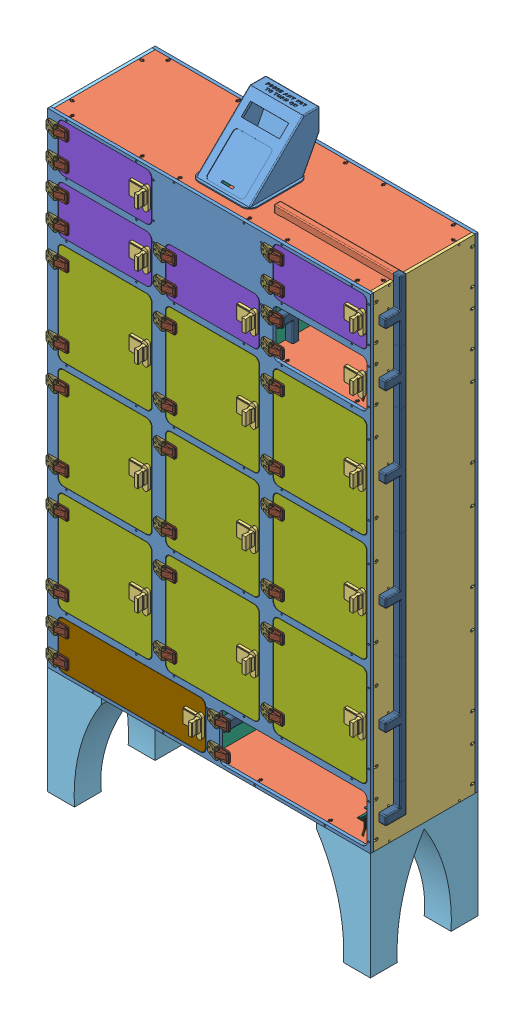
SolidWorks assembly BigAssemb, configuration Default. Lengths in mm.
Overall size (613.29 1199.98 221).
252 component instances, 24 part files, 113 mates.
Components (placement in the parent):
- LargeFront-1: LargeFront [Default] at origin size (600 900 5.8)
- floor + roof-1: floor + roof [only one passthru] at (5.8 100 -188.4) size (588.4 5.8 188.4)
- floor + roof-2: floor + roof [Default] at (5.8 300 -188.4) size (588.4 5.8 188.4)
- floor + roof-3: floor + roof [Default] at (5.8 500 -188.4) size (588.4 5.8 188.4)
- floor + roof-4: floor + roof [Default] at (5.8 700 -188.4) size (588.4 5.8 188.4)
- floor + roof-5: floor + roof [Default] at (5.8 800 -188.4) size (588.4 5.8 188.4)
- right side-1: right side [Default] at (594.2 0 0) size (5.8 900 188.4)
- right(INSIDE200mm)-1: right(INSIDE200mm) [Default] at (194.2 200 -94.2) size (5.8 194.2 188.4)
- right(INSIDE200mm)-2: right(INSIDE200mm) [Default] at (194.2 400 -94.2) size (5.8 194.2 188.4)
- right(INSIDE200mm)-3: right(INSIDE200mm) [Default] at (194.2 600 -94.2) size (5.8 194.2 188.4)
- right(INSIDE200mm)-4: right(INSIDE200mm) [Default] at (394.2 200 -94.2) size (5.8 194.2 188.4)
- right(INSIDE200mm)-5: right(INSIDE200mm) [Default] at (394.2 400 -94.2) size (5.8 194.2 188.4)
- right(INSIDE200mm)-6: right(INSIDE200mm) [Default] at (394.2 600 -94.2) size (5.8 194.2 188.4)
- sides-2: sides [right] at (5.8 0 -188.4) x (-1 0 0) z (0 0 -1) size (5.8 900 188.4)
- right(INSIDE100mm)-7: right(INSIDE100mm) [Default] at (194.2 750 -94.2) size (5.8 94.2 188.4)
- right(INSIDE100mm)-8: right(INSIDE100mm) [top(-5.8)] at (194.2 850 -94.2) size (5.8 88.4 188.4)
- right(INSIDE100mm)-9: right(INSIDE100mm) [Default] at (394.2 750 -94.2) size (5.8 94.2 188.4)
- right(INSIDE100mm)-10: right(INSIDE100mm) [top(no servo)] at (394.2 850 -94.2) size (5.8 88.4 188.4)
- right(INSIDE100mm)-11: right(INSIDE100mm) [Default] at (294.2 50 -94.2) size (5.8 94.2 188.4)
- LargeFront-2: LargeFront [back] at (0 0 -194.2) size (600 900 5.8)
- door(200x200)-1: door(200x200) [Default] at (106.7 200 0) size (173 187.4 5.8)
- door(200x200)-2: door(200x200) [Default] at (106.7 400 0) size (173 187.4 5.8)
- door(200x200)-3: door(200x200) [Default] at (106.7 600 0) size (173 187.4 5.8)
- door(200x200)-4: door(200x200) [Default] at (306.7 200 0) size (173 187.4 5.8)
- door(200x200)-5: door(200x200) [Default] at (306.7 400 0) size (173 187.4 5.8)
- door(200x200)-6: door(200x200) [Default] at (306.7 600 0) size (173 187.4 5.8)
- door(200x200)-7: door(200x200) [Default] at (506.7 200 0) size (173 187.4 5.8)
- door(200x200)-8: door(200x200) [Default] at (506.7 400 0) size (173 187.4 5.8)
- door(200x200)-9: door(200x200) [Default] at (506.7 600 0) size (173 187.4 5.8)
- door(100x200)-1: door(100x200) [Default] at (20.2 750 0) size (173 88.4 5.8)
- door(100x200)-2: door(100x200) [Default] at (20.2 850 0) size (173 88.4 5.8)
- door(100x200)-3: door(100x200) [Default] at (220.2 750 0) size (173 88.4 5.8)
- door(100x200)-4: door(100x200) [Default] at (420.2 750 0) size (173 88.4 5.8) (hidden)
- door(100x200)-5: door(100x200) [Default] at (420.2 850 0) size (173 88.4 5.8)
- door(100x300)-1: door(100x300) [Default] at (20.2 50 0) size (273 87.4 5.8)
- door(100x300)-2: door(100x300) [Default] at (320.2 50 0) size (273 87.4 5.8) (hidden)
- floor + roof-6: floor + roof [roof] at (5.8 894.2 -188.4) size (588.4 5.8 188.4)
- Conduit-9: Conduit [Default] at (600 194.025 -12.141) x (0 0 -1) z (1 0 0) size (38.8 200 13)
- Conduit-10: Conduit [Default] at (600 394.025 -12.141) x (0 0 -1) z (1 0 0) size (38.8 200 13)
- Conduit-11: Conduit [Default] at (600 594.025 -12.141) x (0 0 -1) z (1 0 0) size (38.8 200 13)
- Conduit-12: Conduit [100] at (600 744.025 -12.141) x (0 0 -1) z (1 0 0) size (38.8 100 13)
- Conduit-13: Conduit [top100] at (600 844.025 -12.141) x (0 0 -1) z (1 0 0) size (38.8 113 13)
- Conduit-14: Conduit [Default] at (400 194.025 -12.141) x (0 0 -1) z (1 0 0) size (38.8 200 13)
- Conduit-15: Conduit [Inside200] at (200 194.025 -12.141) x (0 0 -1) z (1 0 0) size (38.8 108.15 13)
- Conduit-17: Conduit [Default] at (400 394.025 -12.141) x (0 0 -1) z (1 0 0) size (38.8 200 13)
- Conduit-18: Conduit [Default] at (200 394.025 -12.141) x (0 0 -1) z (1 0 0) size (38.8 200 13)
- Conduit-20: Conduit [Default] at (400 594.025 -12.141) x (0 0 -1) z (1 0 0) size (38.8 200 13)
- Conduit-21: Conduit [Default] at (200 594.025 -12.141) x (0 0 -1) z (1 0 0) size (38.8 200 13)
- Conduit-23: Conduit [100] at (400 744.025 -12.141) x (0 0 -1) z (1 0 0) size (38.8 100 13)
- Conduit-24: Conduit [100] at (200 744.025 -12.141) x (0 0 -1) z (1 0 0) size (38.8 100 13)
- Conduit-25: Conduit [inside left] at (200 844.025 -12.141) x (0 0 -1) z (1 0 0) size (38.8 71.15 13)
- Conduit-26: Conduit [inside right] at (400 844.025 -12.141) x (0 0 -1) z (1 0 0) size (12 71.15 20.3)
- Conduit-27: Conduit [bottom100] at (600 44.025 -12.141) x (0 0 -1) z (1 0 0) size (38.8 58.15 13)
- hinge in-2: hinge in [Default] at (27.9167 96.333 5.8) x (0 1 0) z (0 0 1) size (20 23.4 8)
- hinge in-3: hinge in [Default] at (27.9167 45.333 6.3536) x (0 1 0) z (0 0 1) size (20 23.4 8)
- hinge in-4: hinge in [Default] at (27.9167 155.833 5.8) x (0 1 0) z (0 0 1) size (20 23.4 8)
- hinge in-5: hinge in [Default] at (27.9167 745.333 5.8) x (0 1 0) z (0 0 1) size (20 23.4 8)
- hinge in-6: hinge in [Default] at (27.9167 796.333 6.3536) x (0 1 0) z (0 0 1) size (20 23.4 8)
- hinge in-7: hinge in [Default] at (27.9167 285.833 5.8) x (0 1 0) z (0 0 1) size (20 23.4 8)
- hinge in-8: hinge in [Default] at (327.9167 96.333 5.8) x (0 1 0) z (0 0 1) size (20 23.4 8)
- hinge in-9: hinge in [Default] at (327.9167 45.333 6.3536) x (0 1 0) z (0 0 1) size (20 23.4 8)
- hinge in-10: hinge in [Default] at (27.9167 485.833 5.8) x (0 1 0) z (0 0 1) size (20 23.4 8)
- hinge in-11: hinge in [Default] at (27.9167 685.833 5.8) x (0 1 0) z (0 0 1) size (20 23.4 8)
- hinge in-12: hinge in [Default] at (227.9167 285.833 5.8) x (0 1 0) z (0 0 1) size (20 23.4 8)
- hinge in-13: hinge in [Default] at (227.9167 485.833 5.8) x (0 1 0) z (0 0 1) size (20 23.4 8)
- hinge in-14: hinge in [Default] at (227.9167 685.833 5.8) x (0 1 0) z (0 0 1) size (20 23.4 8)
- hinge in-15: hinge in [Default] at (427.9167 285.833 5.8) x (0 1 0) z (0 0 1) size (20 23.4 8)
- hinge in-16: hinge in [Default] at (427.9167 485.833 5.8) x (0 1 0) z (0 0 1) size (20 23.4 8)
- hinge in-17: hinge in [Default] at (427.9167 685.833 5.8) x (0 1 0) z (0 0 1) size (20 23.4 8)
- hinge in-18: hinge in [Default] at (27.9167 355.833 5.8) x (0 1 0) z (0 0 1) size (20 23.4 8)
- hinge in-19: hinge in [Default] at (27.9167 555.833 5.8) x (0 1 0) z (0 0 1) size (20 23.4 8)
- hinge in-20: hinge in [Default] at (227.9167 155.833 5.8) x (0 1 0) z (0 0 1) size (20 23.4 8)
- hinge in-21: hinge in [Default] at (227.9167 355.833 5.8) x (0 1 0) z (0 0 1) size (20 23.4 8)
- hinge in-22: hinge in [Default] at (227.9167 555.833 5.8) x (0 1 0) z (0 0 1) size (20 23.4 8)
- hinge in-23: hinge in [Default] at (427.9167 155.833 5.8) x (0 1 0) z (0 0 1) size (20 23.4 8)
- hinge in-24: hinge in [Default] at (427.9167 355.833 5.8) x (0 1 0) z (0 0 1) size (20 23.4 8)
- hinge in-25: hinge in [Default] at (427.9167 555.833 5.8) x (0 1 0) z (0 0 1) size (20 23.4 8)
- hinge in-26: hinge in [Default] at (27.9167 896.333 6.3536) x (0 1 0) z (0 0 1) size (20 23.4 8)
- hinge in-27: hinge in [Default] at (227.9167 796.333 6.3536) x (0 1 0) z (0 0 1) size (20 23.4 8)
- hinge in-28: hinge in [Default] at (427.9167 796.333 6.3536) x (0 1 0) z (0 0 1) size (20 23.4 8)
- hinge in-29: hinge in [Default] at (427.9167 896.333 6.3536) x (0 1 0) z (0 0 1) size (20 23.4 8)
- hinge in-30: hinge in [Default] at (27.9167 845.333 5.8) x (0 1 0) z (0 0 1) size (20 23.4 8)
- hinge in-31: hinge in [Default] at (227.9167 745.333 5.8) x (0 1 0) z (0 0 1) size (20 23.4 8)
- hinge in-32: hinge in [Default] at (427.9167 745.333 5.8) x (0 1 0) z (0 0 1) size (20 23.4 8)
- hinge in-33: hinge in [Default] at (427.9167 845.333 5.8) x (0 1 0) z (0 0 1) size (20 23.4 8)
- hinge out-offset-2: hinge out-offset [Default] at (11.9978 3.6698 5.8) x (0 -1 0) z (0 0 1) size (20 22.9 8)
- hinge out-offset-11: hinge out-offset [Default] at (11.9978 54.6698 5.8) x (0 -1 0) z (0 0 1) size (20 22.9 8)
- hinge out-offset-13: hinge out-offset [Default] at (11.9978 114.1698 5.8) x (0 -1 0) z (0 0 1) size (20 22.9 8)
- hinge out-offset-27: hinge out-offset [Default] at (11.9978 244.1698 5.8) x (0 -1 0) z (0 0 1) size (20 22.9 8)
- hinge out-offset-36: hinge out-offset [Default] at (11.9978 703.6698 5.8) x (0 -1 0) z (0 0 1) size (20 22.9 8)
- hinge out-offset-41: hinge out-offset [Default] at (11.9978 754.6698 5.8) x (0 -1 0) z (0 0 1) size (20 22.9 8)
- hinge out-offset-12: hinge out-offset [Default] at (311.9978 54.6698 5.8) x (0 -1 0) z (0 0 1) size (20 22.9 8)
- hinge out-offset-10: hinge out-offset [Default] at (311.9978 3.6698 5.8) x (0 -1 0) z (0 0 1) size (20 22.9 8)
- hinge out-offset-28: hinge out-offset [Default] at (11.9978 444.1698 5.8) x (0 -1 0) z (0 0 1) size (20 22.9 8)
- hinge out-offset-29: hinge out-offset [Default] at (11.9978 644.1698 5.8) x (0 -1 0) z (0 0 1) size (20 22.9 8)
- hinge out-offset-30: hinge out-offset [Default] at (211.9978 244.1698 5.8) x (0 -1 0) z (0 0 1) size (20 22.9 8)
- hinge out-offset-31: hinge out-offset [Default] at (211.9978 444.1698 5.8) x (0 -1 0) z (0 0 1) size (20 22.9 8)
- hinge out-offset-32: hinge out-offset [Default] at (211.9978 644.1698 5.8) x (0 -1 0) z (0 0 1) size (20 22.9 8)
- hinge out-offset-33: hinge out-offset [Default] at (411.9978 244.1698 5.8) x (0 -1 0) z (0 0 1) size (20 22.9 8)
- hinge out-offset-34: hinge out-offset [Default] at (411.9978 444.1698 5.8) x (0 -1 0) z (0 0 1) size (20 22.9 8)
- hinge out-offset-35: hinge out-offset [Default] at (411.9978 644.1698 5.8) x (0 -1 0) z (0 0 1) size (20 22.9 8)
- hinge out-offset-19: hinge out-offset [Default] at (11.9978 314.1698 5.8) x (0 -1 0) z (0 0 1) size (20 22.9 8)
- hinge out-offset-20: hinge out-offset [Default] at (11.9978 514.1698 5.8) x (0 -1 0) z (0 0 1) size (20 22.9 8)
- hinge out-offset-21: hinge out-offset [Default] at (211.9978 114.1698 5.8) x (0 -1 0) z (0 0 1) size (20 22.9 8)
- hinge out-offset-22: hinge out-offset [Default] at (211.9978 314.1698 5.8) x (0 -1 0) z (0 0 1) size (20 22.9 8)
- hinge out-offset-23: hinge out-offset [Default] at (211.9978 514.1698 5.8) x (0 -1 0) z (0 0 1) size (20 22.9 8)
- hinge out-offset-24: hinge out-offset [Default] at (411.9978 114.1698 5.8) x (0 -1 0) z (0 0 1) size (20 22.9 8)
- hinge out-offset-25: hinge out-offset [Default] at (411.9978 314.1698 5.8) x (0 -1 0) z (0 0 1) size (20 22.9 8)
- hinge out-offset-26: hinge out-offset [Default] at (411.9978 514.1698 5.8) x (0 -1 0) z (0 0 1) size (20 22.9 8)
- hinge out-offset-37: hinge out-offset [Default] at (11.9978 803.6698 5.8) x (0 -1 0) z (0 0 1) size (20 22.9 8)
- hinge out-offset-38: hinge out-offset [Default] at (211.9978 703.6698 5.8) x (0 -1 0) z (0 0 1) size (20 22.9 8)
- hinge out-offset-39: hinge out-offset [Default] at (411.9978 703.6698 5.8) x (0 -1 0) z (0 0 1) size (20 22.9 8)
- hinge out-offset-40: hinge out-offset [Default] at (411.9978 803.6698 5.8) x (0 -1 0) z (0 0 1) size (20 22.9 8)
- hinge out-offset-42: hinge out-offset [Default] at (11.9978 854.6698 5.8) x (0 -1 0) z (0 0 1) size (20 22.9 8)
- hinge out-offset-43: hinge out-offset [Default] at (211.9978 754.6698 5.8) x (0 -1 0) z (0 0 1) size (20 22.9 8)
- hinge out-offset-44: hinge out-offset [Default] at (411.9978 754.6698 5.8) x (0 -1 0) z (0 0 1) size (20 22.9 8)
- hinge out-offset-45: hinge out-offset [Default] at (411.9978 854.6698 5.8) x (0 -1 0) z (0 0 1) size (20 22.9 8)
- floor + roof-7: floor + roof [floor] at (5.8 0 -188.4) size (588.4 5.8 188.4)
- LatchAssemb-1: LatchAssemb [Default] at (610.86 844 -34.641) x (0 0 1) z (0 -1 0) size (59.33 32.5 49.06)
  - servo-1: servo [Default] at origin size (32.1 30.61 12)
  - latch shroud-1: latch shroud [Default] at (-4.95 23.16 0) x (0 1 0) z (-1 0 0) size (13.45 37.8 42.25)
  - latch-1: latch [Default] at (40.4868 27.24 -1.4888) x (0 -1 0) z (0.999992 0 -0.004045) size (4.1 23.3 53.57)
  - servo link-1: servo link [Default] at (5.835 27.45 -6) x (0 1 0) z (-0.897729 0 -0.440549) size (9.3 13.8 26.8)
  - spring-1: spring [Default] at (7.42 23.16 -6) x (0 1 0) z (-0.999998 0 -0.001752) size (4.3 11.4 35.23)
  - Doorspring-1: Doorspring [Default] at (-0.017 30.01 0.1365) x (0.999999 0 -0.00113) z (0 1 0) size (12.89 29.53 2.55)
- LatchAssemb-2: LatchAssemb [Default] at (210.86 844 -34.641) x (0 0 1) z (0 -1 0) size (59.33 32.5 49.06)
  - servo-1: servo [Default] at origin size (32.1 30.61 12)
  - latch shroud-1: latch shroud [Default] at (-4.95 23.16 0) x (0 1 0) z (-1 0 0) size (13.45 37.8 42.25)
  - latch-1: latch [Default] at (40.4868 27.24 -1.4888) x (0 -1 0) z (0.999992 0 -0.004045) size (4.1 23.3 53.57)
  - servo link-1: servo link [Default] at (5.835 27.45 -6) x (0 1 0) z (-0.897729 0 -0.440549) size (9.3 13.8 26.8)
  - spring-1: spring [Default] at (7.42 23.16 -6) x (0 1 0) z (-0.999998 0 -0.001752) size (4.3 11.4 35.23)
  - Doorspring-1: Doorspring [Default] at (-0.017 30.01 0.1365) x (0.999999 0 -0.00113) z (0 1 0) size (12.89 29.53 2.55)
- LatchAssemb-3: LatchAssemb [Default] at (610.86 744 -34.641) x (0 0 1) z (0 -1 0) size (59.33 32.5 49.06)
  - servo-1: servo [Default] at origin size (32.1 30.61 12)
  - latch shroud-1: latch shroud [Default] at (-4.95 23.16 0) x (0 1 0) z (-1 0 0) size (13.45 37.8 42.25)
  - latch-1: latch [Default] at (40.4868 27.24 -1.4888) x (0 -1 0) z (0.999992 0 -0.004045) size (4.1 23.3 53.57)
  - servo link-1: servo link [Default] at (5.835 27.45 -6) x (0 1 0) z (-0.897729 0 -0.440549) size (9.3 13.8 26.8)
  - spring-1: spring [Default] at (7.42 23.16 -6) x (0 1 0) z (-0.999998 0 -0.001752) size (4.3 11.4 35.23)
  - Doorspring-1: Doorspring [Default] at (-0.017 30.01 0.1365) x (0.999999 0 -0.00113) z (0 1 0) size (12.89 29.53 2.55)
- LatchAssemb-4: LatchAssemb [Default] at (410.86 744 -34.641) x (0 0 1) z (0 -1 0) size (59.33 32.5 49.06)
  - servo-1: servo [Default] at origin size (32.1 30.61 12)
  - latch shroud-1: latch shroud [Default] at (-4.95 23.16 0) x (0 1 0) z (-1 0 0) size (13.45 37.8 42.25)
  - latch-1: latch [Default] at (40.4868 27.24 -1.4888) x (0 -1 0) z (0.999992 0 -0.004045) size (4.1 23.3 53.57)
  - servo link-1: servo link [Default] at (5.835 27.45 -6) x (0 1 0) z (-0.897729 0 -0.440549) size (9.3 13.8 26.8)
  - spring-1: spring [Default] at (7.42 23.16 -6) x (0 1 0) z (-0.999998 0 -0.001752) size (4.3 11.4 35.23)
  - Doorspring-1: Doorspring [Default] at (-0.017 30.01 0.1365) x (0.999999 0 -0.00113) z (0 1 0) size (12.89 29.53 2.55)
- LatchAssemb-5: LatchAssemb [Default] at (210.86 744 -34.641) x (0 0 1) z (0 -1 0) size (59.33 32.5 49.06)
  - servo-1: servo [Default] at origin size (32.1 30.61 12)
  - latch shroud-1: latch shroud [Default] at (-4.95 23.16 0) x (0 1 0) z (-1 0 0) size (13.45 37.8 42.25)
  - latch-1: latch [Default] at (40.4868 27.24 -1.4888) x (0 -1 0) z (0.999992 0 -0.004045) size (4.1 23.3 53.57)
  - servo link-1: servo link [Default] at (5.835 27.45 -6) x (0 1 0) z (-0.897729 0 -0.440549) size (9.3 13.8 26.8)
  - spring-1: spring [Default] at (7.42 23.16 -6) x (0 1 0) z (-0.999998 0 -0.001752) size (4.3 11.4 35.23)
  - Doorspring-1: Doorspring [Default] at (-0.017 30.01 0.1365) x (0.999999 0 -0.00113) z (0 1 0) size (12.89 29.53 2.55)
- ScreenMount-1: ScreenMount [Default] at (300 895.2 -70) x (-1 0 0) z (0 0 -1) size (110 107.98 135)
- topConduit-1: topConduit [Default] at (380 900.175 -38.941) size (222 18.8 12)
- knob-1: knob [Default] at (185.7 740.45 5.8) size (35 41.51 21)
- knob-2: knob [Default] at (185.7 840.45 5.8) size (35 41.51 21)
- knob-3: knob [Default] at (385.7 740.45 5.8) size (35 41.51 21)
- knob-4: knob [Default] at (585.7 740.45 5.8) size (35 41.51 21)
- knob-5: knob [Default] at (585.7 840.45 5.8) size (35 41.51 21)
- LatchAssemb-6: LatchAssemb [Default] at (310.86 44 -34.591) x (0 0 1) z (0 -1 0) size (59.33 32.5 49.06)
  - servo-1: servo [Default] at origin size (32.1 30.61 12)
  - latch shroud-1: latch shroud [Default] at (-4.95 23.16 0) x (0 1 0) z (-1 0 0) size (13.45 37.8 42.25)
  - latch-1: latch [Default] at (40.4868 27.24 -1.4888) x (0 -1 0) z (0.999992 0 -0.004045) size (4.1 23.3 53.57)
  - servo link-1: servo link [Default] at (5.835 27.45 -6) x (0 1 0) z (-0.897729 0 -0.440549) size (9.3 13.8 26.8)
  - spring-1: spring [Default] at (7.42 23.16 -6) x (0 1 0) z (-0.999998 0 -0.001752) size (4.3 11.4 35.23)
  - Doorspring-1: Doorspring [Default] at (-0.017 30.01 0.1365) x (0.999999 0 -0.00113) z (0 1 0) size (12.89 29.53 2.55)
- LatchAssemb-7: LatchAssemb [Default] at (610.86 44 -34.591) x (0 0 1) z (0 -1 0) size (59.33 32.5 49.06)
  - servo-1: servo [Default] at origin size (32.1 30.61 12)
  - latch shroud-1: latch shroud [Default] at (-4.95 23.16 0) x (0 1 0) z (-1 0 0) size (13.45 37.8 42.25)
  - latch-1: latch [Default] at (40.4868 27.24 -1.4888) x (0 -1 0) z (0.999992 0 -0.004045) size (4.1 23.3 53.57)
  - servo link-1: servo link [Default] at (5.835 27.45 -6) x (0 1 0) z (-0.897729 0 -0.440549) size (9.3 13.8 26.8)
  - spring-1: spring [Default] at (7.42 23.16 -6) x (0 1 0) z (-0.999998 0 -0.001752) size (4.3 11.4 35.23)
  - Doorspring-1: Doorspring [Default] at (-0.017 30.01 0.1365) x (0.999999 0 -0.00113) z (0 1 0) size (12.89 29.53 2.55)
- LatchAssemb-8: LatchAssemb [Default] at (210.86 194 -34.591) x (0 0 1) z (0 -1 0) size (59.33 32.5 49.06)
  - servo-1: servo [Default] at origin size (32.1 30.61 12)
  - latch shroud-1: latch shroud [Default] at (-4.95 23.16 0) x (0 1 0) z (-1 0 0) size (13.45 37.8 42.25)
  - latch-1: latch [Default] at (40.4868 27.24 -1.4888) x (0 -1 0) z (0.999992 0 -0.004045) size (4.1 23.3 53.57)
  - servo link-1: servo link [Default] at (5.835 27.45 -6) x (0 1 0) z (-0.897729 0 -0.440549) size (9.3 13.8 26.8)
  - spring-1: spring [Default] at (7.42 23.16 -6) x (0 1 0) z (-0.999998 0 -0.001752) size (4.3 11.4 35.23)
  - Doorspring-1: Doorspring [Default] at (-0.017 30.01 0.1365) x (0.999999 0 -0.00113) z (0 1 0) size (12.89 29.53 2.55)
- LatchAssemb-9: LatchAssemb [Default] at (210.86 394 -34.591) x (0 0 1) z (0 -1 0) size (59.33 32.5 49.06)
  - servo-1: servo [Default] at origin size (32.1 30.61 12)
  - latch shroud-1: latch shroud [Default] at (-4.95 23.16 0) x (0 1 0) z (-1 0 0) size (13.45 37.8 42.25)
  - latch-1: latch [Default] at (40.4868 27.24 -1.4888) x (0 -1 0) z (0.999992 0 -0.004045) size (4.1 23.3 53.57)
  - servo link-1: servo link [Default] at (5.835 27.45 -6) x (0 1 0) z (-0.897729 0 -0.440549) size (9.3 13.8 26.8)
  - spring-1: spring [Default] at (7.42 23.16 -6) x (0 1 0) z (-0.999998 0 -0.001752) size (4.3 11.4 35.23)
  - Doorspring-1: Doorspring [Default] at (-0.017 30.01 0.1365) x (0.999999 0 -0.00113) z (0 1 0) size (12.89 29.53 2.55)
- LatchAssemb-10: LatchAssemb [Default] at (210.86 594 -34.591) x (0 0 1) z (0 -1 0) size (59.33 32.5 49.06)
  - servo-1: servo [Default] at origin size (32.1 30.61 12)
  - latch shroud-1: latch shroud [Default] at (-4.95 23.16 0) x (0 1 0) z (-1 0 0) size (13.45 37.8 42.25)
  - latch-1: latch [Default] at (40.4868 27.24 -1.4888) x (0 -1 0) z (0.999992 0 -0.004045) size (4.1 23.3 53.57)
  - servo link-1: servo link [Default] at (5.835 27.45 -6) x (0 1 0) z (-0.897729 0 -0.440549) size (9.3 13.8 26.8)
  - spring-1: spring [Default] at (7.42 23.16 -6) x (0 1 0) z (-0.999998 0 -0.001752) size (4.3 11.4 35.23)
  - Doorspring-1: Doorspring [Default] at (-0.017 30.01 0.1365) x (0.999999 0 -0.00113) z (0 1 0) size (12.89 29.53 2.55)
- LatchAssemb-11: LatchAssemb [Default] at (410.86 194 -34.591) x (0 0 1) z (0 -1 0) size (59.33 32.5 49.06)
  - servo-1: servo [Default] at origin size (32.1 30.61 12)
  - latch shroud-1: latch shroud [Default] at (-4.95 23.16 0) x (0 1 0) z (-1 0 0) size (13.45 37.8 42.25)
  - latch-1: latch [Default] at (40.4868 27.24 -1.4888) x (0 -1 0) z (0.999992 0 -0.004045) size (4.1 23.3 53.57)
  - servo link-1: servo link [Default] at (5.835 27.45 -6) x (0 1 0) z (-0.897729 0 -0.440549) size (9.3 13.8 26.8)
  - spring-1: spring [Default] at (7.42 23.16 -6) x (0 1 0) z (-0.999998 0 -0.001752) size (4.3 11.4 35.23)
  - Doorspring-1: Doorspring [Default] at (-0.017 30.01 0.1365) x (0.999999 0 -0.00113) z (0 1 0) size (12.89 29.53 2.55)
- LatchAssemb-12: LatchAssemb [Default] at (410.86 394 -34.591) x (0 0 1) z (0 -1 0) size (59.33 32.5 49.06)
  - servo-1: servo [Default] at origin size (32.1 30.61 12)
  - latch shroud-1: latch shroud [Default] at (-4.95 23.16 0) x (0 1 0) z (-1 0 0) size (13.45 37.8 42.25)
  - latch-1: latch [Default] at (40.4868 27.24 -1.4888) x (0 -1 0) z (0.999992 0 -0.004045) size (4.1 23.3 53.57)
  - servo link-1: servo link [Default] at (5.835 27.45 -6) x (0 1 0) z (-0.897729 0 -0.440549) size (9.3 13.8 26.8)
  - spring-1: spring [Default] at (7.42 23.16 -6) x (0 1 0) z (-0.999998 0 -0.001752) size (4.3 11.4 35.23)
  - Doorspring-1: Doorspring [Default] at (-0.017 30.01 0.1365) x (0.999999 0 -0.00113) z (0 1 0) size (12.89 29.53 2.55)
- LatchAssemb-13: LatchAssemb [Default] at (410.86 594 -34.591) x (0 0 1) z (0 -1 0) size (59.33 32.5 49.06)
  - servo-1: servo [Default] at origin size (32.1 30.61 12)
  - latch shroud-1: latch shroud [Default] at (-4.95 23.16 0) x (0 1 0) z (-1 0 0) size (13.45 37.8 42.25)
  - latch-1: latch [Default] at (40.4868 27.24 -1.4888) x (0 -1 0) z (0.999992 0 -0.004045) size (4.1 23.3 53.57)
  - servo link-1: servo link [Default] at (5.835 27.45 -6) x (0 1 0) z (-0.897729 0 -0.440549) size (9.3 13.8 26.8)
  - spring-1: spring [Default] at (7.42 23.16 -6) x (0 1 0) z (-0.999998 0 -0.001752) size (4.3 11.4 35.23)
  - Doorspring-1: Doorspring [Default] at (-0.017 30.01 0.1365) x (0.999999 0 -0.00113) z (0 1 0) size (12.89 29.53 2.55)
- LatchAssemb-14: LatchAssemb [Default] at (610.86 194 -34.591) x (0 0 1) z (0 -1 0) size (59.33 32.5 49.06)
  - servo-1: servo [Default] at origin size (32.1 30.61 12)
  - latch shroud-1: latch shroud [Default] at (-4.95 23.16 0) x (0 1 0) z (-1 0 0) size (13.45 37.8 42.25)
  - latch-1: latch [Default] at (40.4868 27.24 -1.4888) x (0 -1 0) z (0.999992 0 -0.004045) size (4.1 23.3 53.57)
  - servo link-1: servo link [Default] at (5.835 27.45 -6) x (0 1 0) z (-0.897729 0 -0.440549) size (9.3 13.8 26.8)
  - spring-1: spring [Default] at (7.42 23.16 -6) x (0 1 0) z (-0.999998 0 -0.001752) size (4.3 11.4 35.23)
  - Doorspring-1: Doorspring [Default] at (-0.017 30.01 0.1365) x (0.999999 0 -0.00113) z (0 1 0) size (12.89 29.53 2.55)
- LatchAssemb-15: LatchAssemb [Default] at (610.86 394 -34.591) x (0 0 1) z (0 -1 0) size (59.33 32.5 49.06)
  - servo-1: servo [Default] at origin size (32.1 30.61 12)
  - latch shroud-1: latch shroud [Default] at (-4.95 23.16 0) x (0 1 0) z (-1 0 0) size (13.45 37.8 42.25)
  - latch-1: latch [Default] at (40.4868 27.24 -1.4888) x (0 -1 0) z (0.999992 0 -0.004045) size (4.1 23.3 53.57)
  - servo link-1: servo link [Default] at (5.835 27.45 -6) x (0 1 0) z (-0.897729 0 -0.440549) size (9.3 13.8 26.8)
  - spring-1: spring [Default] at (7.42 23.16 -6) x (0 1 0) z (-0.999998 0 -0.001752) size (4.3 11.4 35.23)
  - Doorspring-1: Doorspring [Default] at (-0.017 30.01 0.1365) x (0.999999 0 -0.00113) z (0 1 0) size (12.89 29.53 2.55)
- LatchAssemb-16: LatchAssemb [Default] at (610.86 594 -34.591) x (0 0 1) z (0 -1 0) size (59.33 32.5 49.06)
  - servo-1: servo [Default] at origin size (32.1 30.61 12)
  - latch shroud-1: latch shroud [Default] at (-4.95 23.16 0) x (0 1 0) z (-1 0 0) size (13.45 37.8 42.25)
  - latch-1: latch [Default] at (40.4868 27.24 -1.4888) x (0 -1 0) z (0.999992 0 -0.004045) size (4.1 23.3 53.57)
  - servo link-1: servo link [Default] at (5.835 27.45 -6) x (0 1 0) z (-0.897729 0 -0.440549) size (9.3 13.8 26.8)
  - spring-1: spring [Default] at (7.42 23.16 -6) x (0 1 0) z (-0.999998 0 -0.001752) size (4.3 11.4 35.23)
  - Doorspring-1: Doorspring [Default] at (-0.017 30.01 0.1365) x (0.999999 0 -0.00113) z (0 1 0) size (12.89 29.53 2.55)
- knob-6: knob [Default] at (185.7 190.45 5.8) size (35 41.51 21)
- knob-7: knob [Default] at (285.7 40.45 5.8) size (35 41.51 21)
- knob-8: knob [Default] at (385.7 190.45 5.8) size (35 41.51 21)
- knob-9: knob [Default] at (585.7 190.45 5.8) size (35 41.51 21)
- knob-10: knob [Default] at (185.7 390.45 5.8) size (35 41.51 21)
- knob-11: knob [Default] at (385.7 390.45 5.8) size (35 41.51 21)
- knob-12: knob [Default] at (585.7 390.45 5.8) size (35 41.51 21)
- knob-13: knob [Default] at (185.7 590.45 5.8) size (35 41.51 21)
- knob-14: knob [Default] at (385.7 590.45 5.8) size (35 41.51 21)
- knob-15: knob [Default] at (585.7 590.45 5.8) size (35 41.51 21)
- Conduit-28: Conduit [InsideBottom] at (300 44.025 -12.141) x (0 0 -1) z (1 0 0) size (38.8 43.98 13)
- 100x300Conduit-1: 100x300Conduit [Default] at (413 87 -36.941) x (-1 0 0) z (0 0 -1) size (113 14 121)
- Edge Leg-1: Edge Leg [Default] at (0 0 5.8) size (100 200 200)
- Edge Leg-3: Edge Leg [Default] at (600 0 -194.2) x (-1 0 0) z (0 0 -1) size (100 200 200)
- Lidlock-1: Lidlock [Default] at (290.0319 905 -119.9) size (20 5.1 22.1)
Mates (geometry in assembly coordinates):
- Coincident1: coincident aligned: plane of LargeFront-1 through (0 105.8 5.8) normal (0 1 0); plane of floor + roof-1 through (5.8 105.8 0) normal (0 1 0)
- Coincident2: coincident anti-aligned: plane of LargeFront-1 through (0 0 0) normal (0 0 -1); plane of floor + roof-1 through (5.8 100 0) normal (0 0 1)
- Distance1: distance = 5.8 mm aligned: plane of floor + roof-1 through (5.8 100 0) normal (-1 0 0); plane of LargeFront-1 through (0 0 5.8) normal (-1 0 0)
- Coincident4: coincident aligned: plane of floor + roof-5 through (5.8 805.8 0) normal (0 1 0); plane of LargeFront-1 through (0 805.8 5.8) normal (0 1 0)
- Coincident5: coincident anti-aligned: plane of LargeFront-1 through (0 0 0) normal (0 0 -1); plane of floor + roof-5 through (5.8 800 0) normal (0 0 1)
- Distance2: distance = 5.8 mm aligned: plane of floor + roof-5 through (5.8 800 0) normal (-1 0 0); plane of LargeFront-1 through (0 0 5.8) normal (-1 0 0)
- Coincident8: coincident anti-aligned: plane of LargeFront-1 through (0 0 0) normal (0 0 -1); plane of right side-1 through (600 0 0) normal (0 0 1)
- Coincident9: coincident aligned: plane of LargeFront-1 through (0 900 5.8) normal (0 1 0); plane of right side-1 through (600 900 0) normal (0 1 0)
- Coincident10: coincident aligned: plane of LargeFront-1 through (194.2 0 5.8) normal (-1 0 0); plane of right(INSIDE200mm)-1 through (194.2 200 -94.2) normal (-1 0 0)
- Coincident11: coincident anti-aligned: plane of floor + roof-1 through (5.8 105.8 0) normal (0 1 0); plane of right(INSIDE200mm)-1 through (200 105.8 0) normal (0 -1 0)
- Coincident12: coincident anti-aligned: plane of LargeFront-1 through (0 0 0) normal (0 0 -1); plane of right(INSIDE200mm)-1 through (200 105.8 0) normal (0 0 1)
- Coincident16: coincident aligned: plane of LargeFront-1 through (0 900 5.8) normal (0 1 0); plane of sides-2 through (0 900 -188.4) normal (0 1 0)
- Coincident17: coincident aligned: plane of LargeFront-1 through (194.2 0 5.8) normal (-1 0 0); plane of right(INSIDE100mm)-7 through (194.2 750 -94.2) normal (-1 0 0)
- Coincident18: coincident anti-aligned: plane of LargeFront-1 through (0 0 0) normal (0 0 -1); plane of right(INSIDE100mm)-7 through (200 705.8 0) normal (0 0 1)
- Coincident19: coincident anti-aligned: plane of floor + roof-4 through (5.8 705.8 0) normal (0 1 0); plane of right(INSIDE100mm)-7 through (200 705.8 0) normal (0 -1 0)
- Coincident20: coincident aligned: plane of LargeFront-1 through (294.2 0 5.8) normal (-1 0 0); plane of right(INSIDE100mm)-11 through (294.2 50 -94.2) normal (-1 0 0)
- Coincident21: coincident anti-aligned: plane of LargeFront-1 through (0 0 0) normal (0 0 -1); plane of right(INSIDE100mm)-11 through (300 5.8 0) normal (0 0 1)
- Coincident22: coincident anti-aligned: plane of floor + roof-1 through (5.8 100 0) normal (0 -1 0); plane of right(INSIDE100mm)-11 through (294.2 100 -94.2) normal (0 1 0)
- Coincident23: coincident aligned: plane of LargeFront-1 through (600 0 5.8) normal (1 0 0); plane of right side-1 through (600 0 0) normal (1 0 0)
- Coincident24: coincident anti-aligned: plane of right(INSIDE200mm)-3 through (200 505.8 -188.4) normal (0 0 -1); plane of LargeFront-2 through (0 0 -188.4) normal (0 0 1)
- Coincident27: coincident aligned: plane of right side-1 through (600 900 0) normal (0 1 0); plane of LargeFront-2 through (0 900 -188.4) normal (0 1 0)
- ProfileCenter1: profile center = 0 mm aligned: line of door(200x200)-1 through (183.2 293.7 5.8) axis (-1 0 0); circle of LargeFront-1
- ProfileCenter2: profile center = 0 mm aligned: line of door(100x200)-1 through (183.2 794.2 5.8) axis (-1 0 0); circle of LargeFront-1
- ProfileCenter3: profile center = 0 mm aligned: line of door(100x300)-1 through (283.2 93.7 5.8) axis (-1 0 0); circle of LargeFront-1
- Coincident28: coincident aligned: plane of LargeFront-1 through (0 900 5.8) normal (0 1 0); plane of floor + roof-6 through (5.8 900 0) normal (0 1 0)
- Coincident29: coincident anti-aligned: plane of right side-1 through (594.2 0 0) normal (-1 0 0); plane of floor + roof-6 through (594.2 894.2 0) normal (1 0 0)
- Coincident30: coincident anti-aligned: plane of LargeFront-1 through (0 0 0) normal (0 0 -1); plane of floor + roof-6 through (5.8 894.2 0) normal (0 0 1)
- Coincident31: coincident anti-aligned: plane of LargeFront-1 through (0 0 0) normal (0 0 -1); plane of sides-2 through (0 0 0) normal (0 0 1)
- Coincident32: coincident aligned: plane of LargeFront-1 through (0 0 5.8) normal (-1 0 0); plane of sides-2 through (0 0 -188.4) normal (-1 0 0)
- Coincident33: coincident anti-aligned: plane of right side-1 through (600 0 0) normal (1 0 0); plane of Conduit 200 mm-1 through (600 194.025 -12.141) normal (-1 0 0)
- Coincident34: coincident aligned: plane of right side-1 through (600 194.025 0) normal (0 1 0); plane of Conduit 200 mm-1 through (611 194.025 -12.141) normal (0 1 0)
- Coincident35: coincident aligned: plane of right side-1 through (600 0 -12.141) normal (0 0 -1); plane of Conduit 200 mm-1 through (611 194.025 -12.141) normal (0 0 -1)
- Coincident36: coincident aligned: plane of right side-1 through (600 0 -12.141) normal (0 0 -1); plane of Conduit-9 through (611 194.025 -12.141) normal (0 0 -1)
- Coincident37: coincident anti-aligned: plane of right side-1 through (600 0 0) normal (1 0 0); plane of Conduit-9 through (600 194.025 -12.141) normal (-1 0 0)
- Coincident38: coincident aligned: plane of right side-1 through (600 194.025 0) normal (0 1 0); plane of Conduit-9 through (611 194.025 -12.141) normal (0 1 0)
- Coincident39: coincident aligned: plane of right side-1 through (600 744.025 0) normal (0 1 0); plane of Conduit-12 through (611 744.025 -12.141) normal (0 1 0)
- Coincident40: coincident anti-aligned: plane of right side-1 through (600 0 0) normal (1 0 0); plane of Conduit-12 through (600 744.025 -12.141) normal (-1 0 0)
- Coincident41: coincident aligned: plane of Conduit-11 through (613 500.175 -48.941) normal (0 0 -1); plane of Conduit-12 through (613 700.175 -48.941) normal (0 0 -1)
- Coincident42: coincident aligned: plane of right(INSIDE200mm)-4 through (393.65 205.975 -12.141) normal (0 0 -1); plane of Conduit-14 through (411 194.025 -12.141) normal (0 0 -1)
- Coincident43: coincident anti-aligned: plane of right(INSIDE200mm)-4 through (400 200 -94.2) normal (1 0 0); plane of Conduit-14 through (400 194.025 -12.141) normal (-1 0 0)
- Coincident44: coincident aligned: plane of right(INSIDE200mm)-4 through (393.65 194.025 -12.141) normal (0 1 0); plane of Conduit-14 through (411 194.025 -12.141) normal (0 1 0)
- Coincident45: coincident aligned: plane of right(INSIDE100mm)-9 through (393.65 744.025 -12.141) normal (0 1 0); plane of Conduit-23 through (411 744.025 -12.141) normal (0 1 0)
- Coincident46: coincident anti-aligned: plane of right(INSIDE100mm)-9 through (400 750 -94.2) normal (1 0 0); plane of Conduit-23 through (400 744.025 -12.141) normal (-1 0 0)
- Coincident47: coincident aligned: plane of Conduit-20 through (413 500.175 -48.941) normal (0 0 -1); plane of Conduit-23 through (413 700.175 -48.941) normal (0 0 -1)
- Coincident48: coincident aligned: plane of right side-1 through (600 44.025 0) normal (0 1 0); plane of Conduit-27 through (611 44.025 -12.141) normal (0 1 0)
- Coincident49: coincident anti-aligned: plane of right side-1 through (600 0 0) normal (1 0 0); plane of Conduit-27 through (600 44.025 -12.141) normal (-1 0 0)
- Coincident50: coincident aligned: plane of right side-1 through (600 0 -12.141) normal (0 0 -1); plane of Conduit-27 through (611 44.025 -12.141) normal (0 0 -1)
- Coincident52: coincident anti-aligned: plane of door(100x300)-1 through (283.2 83.7 5.8) normal (0 0 1); plane of hinge in-2 through (27.9167 96.333 5.8) normal (0 0 -1)
- Parallel1: parallel aligned: line of door(100x300)-1 through (20.2 83.7 5.8) axis (0 -1 0); line of hinge in-2 through (20.203 70.7028 7.7259) axis (0 -1 0)
- Concentric2: concentric aligned: cylinder of door(100x300)-1 through (37.2 68.5 0) axis (0 0 1) radius 1.55; cylinder of hinge in-2 through (37.2 68.5 0.9917) axis (0 0 1) radius 1.6
- Concentric3: concentric aligned: cylinder of door(100x300)-1 through (37.2 17.5 0) axis (0 0 1) radius 1.55; cylinder of hinge in-3 through (37.2 17.5 1.5453) axis (0 0 1) radius 1.6
- Parallel2: parallel aligned: plane of door(100x300)-1 through (20.2 83.7 5.8) normal (-1 0 0); plane of hinge in-3 through (20.203 45.333 6.3536) normal (-1 0 0)
- Concentric4: concentric aligned: cylinder of door(200x200)-1 through (37.2 128 0) axis (0 0 1) radius 1.55; cylinder of hinge in-4 through (37.2 128 0.9917) axis (0 0 1) radius 1.6
- Parallel3: parallel aligned: plane of door(200x200)-1 through (20.2 283.7 5.8) normal (-1 0 0); plane of hinge in-4 through (20.203 155.833 5.8) normal (-1 0 0)
- Coincident57: coincident anti-aligned: plane of door(200x200)-1 through (183.2 283.7 5.8) normal (0 0 1); plane of hinge in-4 through (27.9167 155.833 5.8) normal (0 0 -1)
- Concentric5: concentric aligned: cylinder of door(200x200)-1 through (37.2 258 0) axis (0 0 1) radius 1.55; cylinder of hinge in-7 through (37.2 258 0.9917) axis (0 0 1) radius 1.6
- Parallel4: parallel aligned: plane of door(200x200)-1 through (20.2 283.7 5.8) normal (-1 0 0); plane of hinge in-7 through (20.203 285.833 5.8) normal (-1 0 0)
- Coincident59: coincident anti-aligned: plane of door(200x200)-1 through (183.2 283.7 5.8) normal (0 0 1); plane of hinge in-7 through (27.9167 285.833 5.8) normal (0 0 -1)
- Concentric6: concentric aligned: cylinder of door(100x200)-1 through (37.2 717.5 0) axis (0 0 1) radius 1.55; cylinder of hinge in-5 through (37.2 717.5 0.9917) axis (0 0 1) radius 1.6
- Parallel5: parallel aligned: plane of door(100x200)-1 through (20.2 784.2 5.8) normal (-1 0 0); plane of hinge in-5 through (20.203 745.333 5.8) normal (-1 0 0)
- Coincident61: coincident anti-aligned: plane of door(100x200)-1 through (183.2 784.2 5.8) normal (0 0 1); plane of hinge in-5 through (27.9167 745.333 5.8) normal (0 0 -1)
- Concentric7: concentric aligned: cylinder of door(100x200)-1 through (37.2 768.5 0) axis (0 0 1) radius 1.55; cylinder of hinge in-6 through (37.2 768.5 1.5453) axis (0 0 1) radius 1.6
- Parallel6: parallel aligned: plane of door(100x200)-1 through (20.2 784.2 5.8) normal (-1 0 0); plane of hinge in-6 through (20.203 796.333 6.3536) normal (-1 0 0)
- Concentric8: concentric aligned: cylinder of LargeFront-1 through (2.9 24.5 5.8) axis (0 0 -1) radius 1.5; circle of hinge out-offset-2
- Parallel7: parallel aligned: plane of LargeFront-1 through (0 0 5.8) normal (-1 0 0); plane of hinge out-offset-2 through (-0.2885 3.6698 5.8) normal (-1 0 0)
- Coincident65: coincident: point of LargeFront-1; unknown of hinge out-offset-2
- Concentric9: concentric anti-aligned: cylinder of LargeFront-1 through (2.9 75.5 5.8) axis (0 0 -1) radius 1.5; cylinder of hinge out-offset-11 through (2.9 75.5 -1.4125) axis (0 0 1) radius 1.55
- Parallel8: parallel aligned: plane of LargeFront-1 through (0 0 5.8) normal (-1 0 0); plane of hinge out-offset-11 through (-0.2885 54.6698 5.8) normal (-1 0 0)
- Coincident67: coincident: plane of LargeFront-1 through (0 0 5.8) normal (0 0 1); line of hinge out-offset-11 through (0.6158 83.3679 5.8) axis (0.372177 -0.928162 0)
- Concentric10: concentric anti-aligned: cylinder of LargeFront-1 through (2.9 135 5.8) axis (0 0 -1) radius 1.5; cylinder of hinge out-offset-13 through (2.9 135 -1.4125) axis (0 0 1) radius 1.55
- Parallel9: parallel aligned: plane of LargeFront-1 through (0 0 5.8) normal (-1 0 0); plane of hinge out-offset-13 through (-0.2885 114.1698 5.8) normal (-1 0 0)
- Coincident69: coincident: plane of LargeFront-1 through (0 0 5.8) normal (0 0 1); line of hinge out-offset-13 through (2.1227 137.4286 5.8) axis (-0.561696 0.827344 0)
- Concentric11: concentric anti-aligned: circle of LargeFront-1; cylinder of hinge out-offset-27 through (2.9 265 -1.4125) axis (0 0 1) radius 1.55
- Parallel10: parallel aligned: plane of LargeFront-1 through (0 0 5.8) normal (-1 0 0); plane of hinge out-offset-27 through (-0.2885 244.1698 5.8) normal (-1 0 0)
- Coincident71: coincident: plane of LargeFront-1 through (0 0 5.8) normal (0 0 1); line of hinge out-offset-27 through (13.4245 264.6402 5.8) axis (0.514687 -0.857378 0)
- Concentric12: concentric anti-aligned: cylinder of LargeFront-1 through (2.9 724.5 5.8) axis (0 0 -1) radius 1.5; cylinder of hinge out-offset-36 through (2.9 724.5 -1.4125) axis (0 0 1) radius 1.55
- Parallel11: parallel aligned: plane of LargeFront-1 through (0 0 5.8) normal (-1 0 0); plane of hinge out-offset-36 through (-0.2885 703.6698 5.8) normal (-1 0 0)
- Coincident73: coincident anti-aligned: plane of LargeFront-1 through (0 0 5.8) normal (0 0 1); plane of hinge out-offset-36 through (11.9978 703.6698 5.8) normal (0 0 -1)
- Concentric13: concentric anti-aligned: cylinder of LargeFront-1 through (2.9 775.5 5.8) axis (0 0 -1) radius 1.5; cylinder of hinge out-offset-41 through (2.9 775.5 -1.4125) axis (0 0 1) radius 1.55
- Coincident74: coincident anti-aligned: plane of LargeFront-1 through (0 0 5.8) normal (0 0 1); plane of hinge out-offset-41 through (11.9978 754.6698 5.8) normal (0 0 -1)
- Parallel12: parallel aligned: plane of LargeFront-1 through (0 0 5.8) normal (-1 0 0); plane of hinge out-offset-41 through (-0.2885 754.6698 5.8) normal (-1 0 0)
- Coincident76: coincident anti-aligned: plane of right(INSIDE100mm)-11 through (300 5.8 0) normal (0 -1 0); plane of floor + roof-7 through (5.8 5.8 0) normal (0 1 0)
- Coincident77: coincident anti-aligned: plane of LargeFront-2 through (0 0 -188.4) normal (0 0 1); plane of floor + roof-7 through (5.8 0 -188.4) normal (0 0 -1)
- Coincident78: coincident anti-aligned: plane of sides-2 through (5.8 0 -188.4) normal (1 0 0); plane of floor + roof-7 through (5.8 0 0) normal (-1 0 0)
- Coincident183: coincident anti-aligned: plane of right side-1 through (594.2 0 0) normal (-1 0 0); plane of LatchAssemb-1/latch shroud-1 through (594.2 844 -39.591) normal (1 0 0)
- Concentric119: concentric anti-aligned: cylinder of right side-1 through (600 839 -27.221) axis (-1 0 0) radius 1.5; cylinder of LatchAssemb-1/latch shroud-1 through (583.5988 839 -27.221) axis (1 0 0) radius 1.45
- Parallel14: parallel anti-aligned: plane of floor + roof-5 through (5.8 800 0) normal (0 -1 0); plane of LatchAssemb-3/latch shroud-1 through (594.2 761 -39.591) normal (0 1 0)
- Parallel15: parallel aligned: plane of LargeFront-1 through (0 0 5.8) normal (0 0 1); plane of door(100x200)-1 through (183.2 784.2 5.8) normal (0 0 1)
- ProfileCenter4: profile center = 0 mm: circle of floor + roof-6; circle of ScreenMount-1
- Coincident184: coincident anti-aligned: plane of Conduit-13 through (600 844.025 -12.141) normal (-1 0 0); plane of topConduit-1 through (600 900.175 -38.941) normal (1 0 0)
- Coincident185: coincident aligned: plane of Conduit-13 through (600 913.175 -12.141) normal (0 1 0); plane of topConduit-1 through (600 913.175 -38.941) normal (0 1 0)
- Coincident186: coincident aligned: plane of Conduit-13 through (611 844.025 -36.941) normal (0 0 1); plane of topConduit-1 through (600 900.175 -36.941) normal (0 0 1)
- Concentric120: concentric aligned: circle of door(100x200)-1; circle of knob-1
- Concentric121: concentric anti-aligned: cylinder of door(100x200)-1 through (185.7 766.45 0) axis (0 0 1) radius 1.55; cylinder of knob-1 through (185.7 766.45 10.8) axis (0 0 -1) radius 1.45
- Coincident187: coincident anti-aligned: plane of door(100x200)-1 through (183.2 784.2 5.8) normal (0 0 1); plane of knob-1 through (185.7 740.45 5.8) normal (0 0 -1)
- ProfileCenter5: profile center = 0 mm anti-aligned: line of LatchAssemb-6/latch shroud-1 through (294.2 56 -39.541) axis (0 0 1); line of right(INSIDE100mm)-11 through (294.2 44.025 -12.141) axis (0 1 0)
- ProfileCenter6: profile center = 0 mm anti-aligned: line of LatchAssemb-8/latch shroud-1 through (194.2 206 -39.541) axis (0 0 1); line of right(INSIDE200mm)-1 through (194.2 205.975 -12.141) axis (0 0 -1)
- Concentric122: concentric aligned: circle of door(100x300)-1; circle of knob-7
- Concentric123: concentric anti-aligned: circle of door(100x300)-1; cylinder of knob-7 through (285.7 66.45 10.8) axis (0 0 -1) radius 1.45
- Concentric124: concentric aligned: circle of door(200x200)-1; circle of knob-6
- Coincident188: coincident anti-aligned: plane of door(200x200)-1 through (183.2 283.7 5.8) normal (0 0 1); plane of knob-6 through (185.7 190.45 5.8) normal (0 0 -1)
- Concentric125: concentric anti-aligned: cylinder of door(200x200)-1 through (185.7 216.45 0) axis (0 0 1) radius 1.55; cylinder of knob-6 through (185.7 216.45 10.8) axis (0 0 -1) radius 1.45
- Coincident189: coincident aligned: plane of Conduit-14 through (411 194.025 -12.141) normal (-1 0 0); plane of 100x300Conduit-1 through (411 100 -36.941) normal (-1 0 0)
- Coincident190: coincident anti-aligned: plane of floor + roof-1 through (5.8 100 0) normal (0 -1 0); plane of 100x300Conduit-1 through (413 100 -36.941) normal (0 1 0)
- Coincident191: coincident aligned: plane of Conduit-28 through (311 44.025 -38.941) normal (0 0 -1); plane of 100x300Conduit-1 through (413 89 -38.941) normal (0 0 -1)
- Coincident192: coincident anti-aligned: plane of door(100x300)-1 through (283.2 83.7 5.8) normal (0 0 1); plane of knob-7 through (285.7 40.45 5.8) normal (0 0 -1)
- Coincident193: coincident aligned: plane of LargeFront-1 through (0 0 5.8) normal (0 0 1); plane of Edge Leg-1 through (0 -200 5.8) normal (0 0 1)
- Coincident194: coincident aligned: plane of sides-2 through (0 0 -188.4) normal (-1 0 0); plane of Edge Leg-1 through (0 -200 5.8) normal (-1 0 0)
- Coincident195: coincident anti-aligned: plane of floor + roof-7 through (5.8 0 0) normal (0 -1 0); plane of Edge Leg-1 through (0 0 5.8) normal (0 1 0)
- Coincident196: coincident anti-aligned: plane of ScreenMount-1 through (300 902 -70) normal (0 1 0); plane of Lidlock-1 through (310.0319 902 -119.9) normal (0 -1 0)
- Coincident197: coincident anti-aligned: plane of floor + roof-6 through (5.8 900 0) normal (0 1 0); plane of ScreenMount-1 through (300 900 -70) normal (0 -1 0)
- Coincident198: coincident anti-aligned: plane of ScreenMount-1 through (300 900 -125) normal (0 0 -1); plane of Lidlock-1 through (310.0319 905 -125) normal (0 0 1)
- Coincident199: coincident anti-aligned: plane of floor + roof-6 through (5.8 752.7786 -120) normal (0 0 1); plane of ScreenMount-1 through (250 902 -120) normal (0 0 -1)
